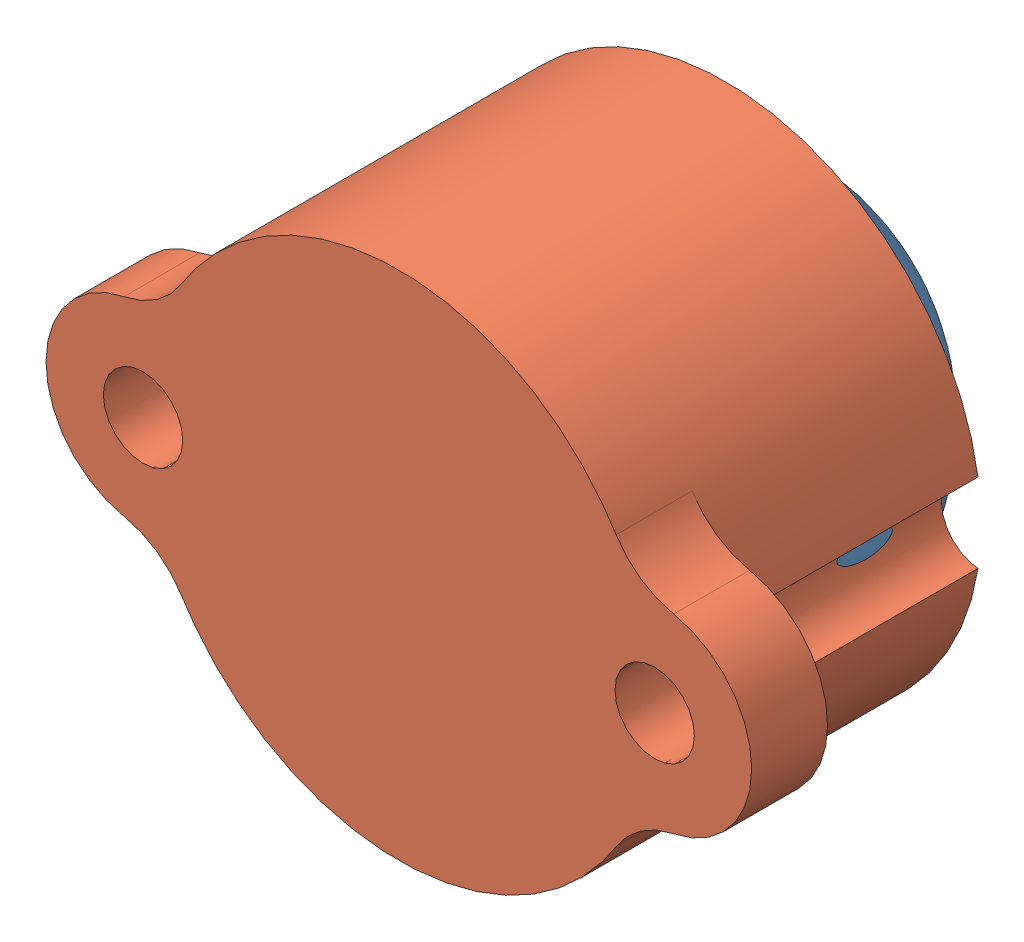
SolidWorks assembly sroller, configuration Default. Lengths in mm.
Overall size (20.32 14.73 13.46).
2 component instances, 2 part files, 0 mates.
Components (placement in the parent):
- boule scroller-1: boule scroller [Default] at (-35.481 -6.7783 23.3279) size (12.55 12.55 12.55)
- scroll_-1: scroll_ [Défaut] at (-35.481 -6.7783 21.1181) size (20.32 14.73 9.4)
